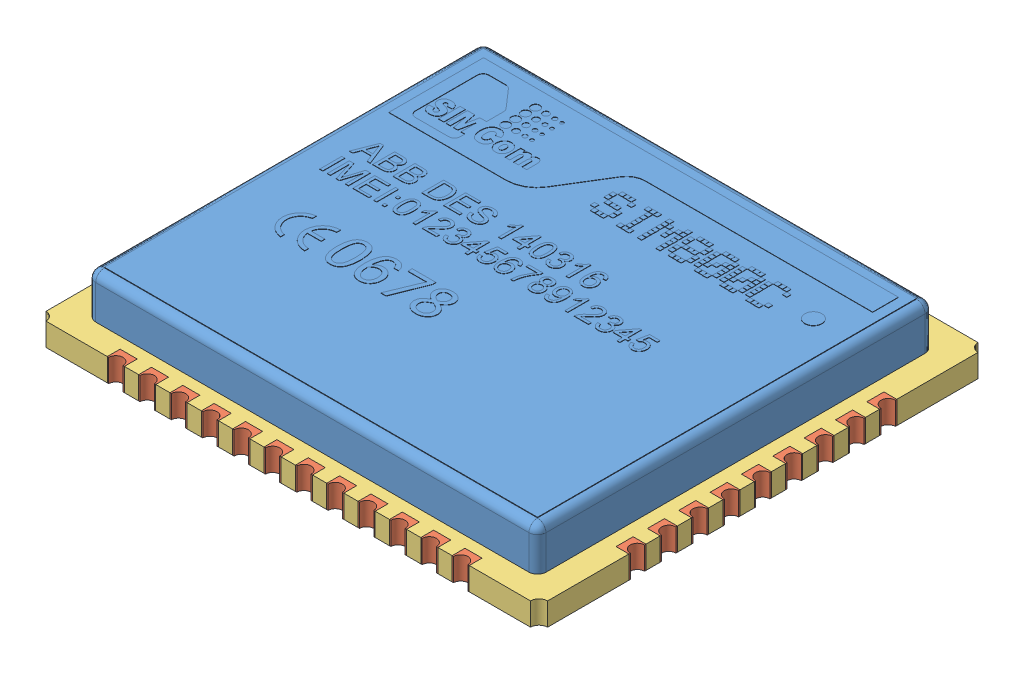
SolidWorks assembly User Library-SIM800C-1, configuration Défaut. Lengths in mm.
Overall size (17.6 2.34 15.7).
44 component instances, 3 part files, 128 mates.
Components (placement in the parent):
- User Library-SIM800C-1_SIM800C_Cup-1: User Library-SIM800C-1_SIM800C_Cup [Défaut] at (-74.7573 31.9435 0) size (15.8 1.53 13.9)
- User Library-SIM800C-1_SIM800C_pads-1: User Library-SIM800C-1_SIM800C_pads [Défaut] at (-80.8082 31.9435 -7.6815) x (1 0 0) z (0 0 -1) size (0.6 0.8 0.45)
- User Library-SIM800C-1_SIM800C_pcb-1: User Library-SIM800C-1_SIM800C_pcb [Défaut] at (-71.1269 31.9435 3.3608) x (1 0 0) z (0 0 -1) size (17.6 0.81 15.7)
- User Library-SIM800C-1_SIM800C_pads-2: User Library-SIM800C-1_SIM800C_pads [Défaut] at (-78.6082 31.9435 -7.6815) x (1 0 0) z (0 0 -1) size (0.6 0.8 0.45)
- User Library-SIM800C-1_SIM800C_pads-3: User Library-SIM800C-1_SIM800C_pads [Défaut] at (-79.7082 31.9435 -7.6815) x (1 0 0) z (0 0 -1) size (0.6 0.8 0.45)
- User Library-SIM800C-1_SIM800C_pads-4: User Library-SIM800C-1_SIM800C_pads [Défaut] at (-77.5082 31.9435 -7.6815) x (1 0 0) z (0 0 -1) size (0.6 0.8 0.45)
- User Library-SIM800C-1_SIM800C_pads-5: User Library-SIM800C-1_SIM800C_pads [Défaut] at (-76.4082 31.9435 -7.6815) x (1 0 0) z (0 0 -1) size (0.6 0.8 0.45)
- User Library-SIM800C-1_SIM800C_pads-6: User Library-SIM800C-1_SIM800C_pads [Défaut] at (-75.3082 31.9435 -7.6815) x (1 0 0) z (0 0 -1) size (0.6 0.8 0.45)
- User Library-SIM800C-1_SIM800C_pads-7: User Library-SIM800C-1_SIM800C_pads [Défaut] at (-74.2082 31.9435 -7.6815) x (1 0 0) z (0 0 -1) size (0.6 0.8 0.45)
- User Library-SIM800C-1_SIM800C_pads-8: User Library-SIM800C-1_SIM800C_pads [Défaut] at (-73.1082 31.9435 -7.6815) x (1 0 0) z (0 0 -1) size (0.6 0.8 0.45)
- User Library-SIM800C-1_SIM800C_pads-9: User Library-SIM800C-1_SIM800C_pads [Défaut] at (-72.0082 31.9435 -7.6815) x (1 0 0) z (0 0 -1) size (0.6 0.8 0.45)
- User Library-SIM800C-1_SIM800C_pads-10: User Library-SIM800C-1_SIM800C_pads [Défaut] at (-70.9082 31.9435 -7.6815) x (1 0 0) z (0 0 -1) size (0.6 0.8 0.45)
- User Library-SIM800C-1_SIM800C_pads-11: User Library-SIM800C-1_SIM800C_pads [Défaut] at (-69.8082 31.9435 -7.6815) x (1 0 0) z (0 0 -1) size (0.6 0.8 0.45)
- User Library-SIM800C-1_SIM800C_pads-12: User Library-SIM800C-1_SIM800C_pads [Défaut] at (-68.7082 31.9435 -7.6815) x (1 0 0) z (0 0 -1) size (0.6 0.8 0.45)
- User Library-SIM800C-1_SIM800C_pads-14: User Library-SIM800C-1_SIM800C_pads [Défaut] at (-66.1832 31.9435 -4.4565) x (0 0 1) z (1 0 0) size (0.6 0.8 0.45)
- User Library-SIM800C-1_SIM800C_pads-15: User Library-SIM800C-1_SIM800C_pads [Défaut] at (-66.1832 31.9435 -3.3565) x (0 0 1) z (1 0 0) size (0.6 0.8 0.45)
- User Library-SIM800C-1_SIM800C_pads-16: User Library-SIM800C-1_SIM800C_pads [Défaut] at (-66.1832 31.1435 -2.2565) x (0 0 -1) z (1 0 0) size (0.6 0.8 0.45)
- User Library-SIM800C-1_SIM800C_pads-17: User Library-SIM800C-1_SIM800C_pads [Défaut] at (-66.1832 31.9435 -1.1565) x (0 0 1) z (1 0 0) size (0.6 0.8 0.45)
- User Library-SIM800C-1_SIM800C_pads-18: User Library-SIM800C-1_SIM800C_pads [Défaut] at (-66.1832 31.9435 -0.0565) x (0 0 1) z (1 0 0) size (0.6 0.8 0.45)
- User Library-SIM800C-1_SIM800C_pads-19: User Library-SIM800C-1_SIM800C_pads [Défaut] at (-66.1832 31.9435 1.0435) x (0 0 1) z (1 0 0) size (0.6 0.8 0.45)
- User Library-SIM800C-1_SIM800C_pads-20: User Library-SIM800C-1_SIM800C_pads [Défaut] at (-66.1832 31.9435 2.1435) x (0 0 1) z (1 0 0) size (0.6 0.8 0.45)
- User Library-SIM800C-1_SIM800C_pads-21: User Library-SIM800C-1_SIM800C_pads [Défaut] at (-66.1832 31.9435 3.2435) x (0 0 1) z (1 0 0) size (0.6 0.8 0.45)
- User Library-SIM800C-1_SIM800C_pads-22: User Library-SIM800C-1_SIM800C_pads [Défaut] at (-66.1832 31.9435 4.3435) x (0 0 1) z (1 0 0) size (0.6 0.8 0.45)
- User Library-SIM800C-1_SIM800C_pads-23: User Library-SIM800C-1_SIM800C_pads [Défaut] at (-83.3332 31.9435 -4.4565) x (0 0 -1) z (-1 0 0) size (0.6 0.8 0.45)
- User Library-SIM800C-1_SIM800C_pads-24: User Library-SIM800C-1_SIM800C_pads [Défaut] at (-83.3332 31.1435 -3.3565) x (0 0 1) z (-1 0 0) size (0.6 0.8 0.45)
- User Library-SIM800C-1_SIM800C_pads-25: User Library-SIM800C-1_SIM800C_pads [Défaut] at (-83.3332 31.1435 -2.2565) x (0 0 1) z (-1 0 0) size (0.6 0.8 0.45)
- User Library-SIM800C-1_SIM800C_pads-26: User Library-SIM800C-1_SIM800C_pads [Défaut] at (-83.3332 31.1435 -1.1565) x (0 0 1) z (-1 0 0) size (0.6 0.8 0.45)
- User Library-SIM800C-1_SIM800C_pads-27: User Library-SIM800C-1_SIM800C_pads [Défaut] at (-83.3332 31.1435 -0.0565) x (0 0 1) z (-1 0 0) size (0.6 0.8 0.45)
- User Library-SIM800C-1_SIM800C_pads-28: User Library-SIM800C-1_SIM800C_pads [Défaut] at (-83.3332 31.1435 1.0435) x (0 0 1) z (-1 0 0) size (0.6 0.8 0.45)
- User Library-SIM800C-1_SIM800C_pads-29: User Library-SIM800C-1_SIM800C_pads [Défaut] at (-83.3332 31.1435 2.1435) x (0 0 1) z (-1 0 0) size (0.6 0.8 0.45)
- User Library-SIM800C-1_SIM800C_pads-30: User Library-SIM800C-1_SIM800C_pads [Défaut] at (-83.3332 31.1435 3.2435) x (0 0 1) z (-1 0 0) size (0.6 0.8 0.45)
- User Library-SIM800C-1_SIM800C_pads-31: User Library-SIM800C-1_SIM800C_pads [Défaut] at (-83.3332 31.1435 4.3435) x (0 0 1) z (-1 0 0) size (0.6 0.8 0.45)
- User Library-SIM800C-1_SIM800C_pads-32: User Library-SIM800C-1_SIM800C_pads [Défaut] at (-80.8082 31.9435 7.5685) x (-1 0 0) z (0 0 1) size (0.6 0.8 0.45)
- User Library-SIM800C-1_SIM800C_pads-33: User Library-SIM800C-1_SIM800C_pads [Défaut] at (-79.7082 31.1435 7.5685) size (0.6 0.8 0.45)
- User Library-SIM800C-1_SIM800C_pads-34: User Library-SIM800C-1_SIM800C_pads [Défaut] at (-78.6082 31.9435 7.5685) x (-1 0 0) z (0 0 1) size (0.6 0.8 0.45)
- User Library-SIM800C-1_SIM800C_pads-35: User Library-SIM800C-1_SIM800C_pads [Défaut] at (-77.5082 31.9435 7.5685) x (-1 0 0) z (0 0 1) size (0.6 0.8 0.45)
- User Library-SIM800C-1_SIM800C_pads-36: User Library-SIM800C-1_SIM800C_pads [Défaut] at (-76.4082 31.1435 7.5685) size (0.6 0.8 0.45)
- User Library-SIM800C-1_SIM800C_pads-37: User Library-SIM800C-1_SIM800C_pads [Défaut] at (-75.3082 31.1435 7.5685) size (0.6 0.8 0.45)
- User Library-SIM800C-1_SIM800C_pads-38: User Library-SIM800C-1_SIM800C_pads [Défaut] at (-74.2082 31.1435 7.5685) size (0.6 0.8 0.45)
- User Library-SIM800C-1_SIM800C_pads-39: User Library-SIM800C-1_SIM800C_pads [Défaut] at (-73.1082 31.1435 7.5685) size (0.6 0.8 0.45)
- User Library-SIM800C-1_SIM800C_pads-40: User Library-SIM800C-1_SIM800C_pads [Défaut] at (-72.0082 31.1435 7.5685) size (0.6 0.8 0.45)
- User Library-SIM800C-1_SIM800C_pads-41: User Library-SIM800C-1_SIM800C_pads [Défaut] at (-70.9082 31.1435 7.5685) size (0.6 0.8 0.45)
- User Library-SIM800C-1_SIM800C_pads-42: User Library-SIM800C-1_SIM800C_pads [Défaut] at (-69.8082 31.1435 7.5685) size (0.6 0.8 0.45)
- User Library-SIM800C-1_SIM800C_pads-43: User Library-SIM800C-1_SIM800C_pads [Défaut] at (-68.7082 31.1435 7.5685) size (0.6 0.8 0.45)
Mates (geometry in assembly coordinates):
- Coïncidente1: coincident: plane of User Library-SIM800C-1_SIM800C_pads-1 through (-81.1082 31.1435 -7.4565) normal (0 0 1); plane of User Library-SIM800C-1_SIM800C_pcb-1 through (-71.1269 31.1435 -7.4565) normal (0 0 -1)
- Coïncidente2: coincident: plane of User Library-SIM800C-1_SIM800C_pads-1 through (-80.5082 31.1435 -7.4565) normal (1 0 0); plane of User Library-SIM800C-1_SIM800C_pcb-1 through (-80.5082 31.1435 3.3608) normal (-1 0 0)
- Coïncidente3: coincident: plane of User Library-SIM800C-1_SIM800C_pads-1 through (-80.8082 31.1435 -7.9065) normal (0 -1 0); plane of User Library-SIM800C-1_SIM800C_pcb-1 through (-71.1269 31.1435 3.3608) normal (0 -1 0)
- Coïncidente13: coincident: plane of User Library-SIM800C-1_SIM800C_pcb-1 through (-71.1269 31.1435 -7.4565) normal (0 0 -1); plane of User Library-SIM800C-1_SIM800C_pads-3 through (-80.0082 31.1435 -7.4565) normal (0 0 1)
- Coïncidente14: coincident: plane of User Library-SIM800C-1_SIM800C_pcb-1 through (-79.4082 31.1435 3.3608) normal (-1 0 0); plane of User Library-SIM800C-1_SIM800C_pads-3 through (-79.4082 31.1435 -7.4565) normal (1 0 0)
- Coïncidente15: coincident: plane of User Library-SIM800C-1_SIM800C_pcb-1 through (-71.1269 31.1435 3.3608) normal (0 -1 0); plane of User Library-SIM800C-1_SIM800C_pads-3 through (-79.7082 31.1435 -7.9065) normal (0 -1 0)
- Coïncidente16: coincident: plane of User Library-SIM800C-1_SIM800C_pcb-1 through (-71.1269 31.1435 -7.4565) normal (0 0 -1); plane of User Library-SIM800C-1_SIM800C_pads-2 through (-78.9082 31.1435 -7.4565) normal (0 0 1)
- Coïncidente17: coincident: plane of User Library-SIM800C-1_SIM800C_pcb-1 through (-78.3082 31.1435 3.3608) normal (-1 0 0); plane of User Library-SIM800C-1_SIM800C_pads-2 through (-78.3082 31.1435 -7.4565) normal (1 0 0)
- Coïncidente18: coincident: plane of User Library-SIM800C-1_SIM800C_pcb-1 through (-71.1269 31.1435 3.3608) normal (0 -1 0); plane of User Library-SIM800C-1_SIM800C_pads-2 through (-78.6082 31.1435 -7.9065) normal (0 -1 0)
- Coïncidente19: coincident: plane of User Library-SIM800C-1_SIM800C_pcb-1 through (-71.1269 31.1435 -7.4565) normal (0 0 -1); plane of User Library-SIM800C-1_SIM800C_pads-4 through (-77.8082 31.1435 -7.4565) normal (0 0 1)
- Coïncidente20: coincident: plane of User Library-SIM800C-1_SIM800C_pcb-1 through (-77.2082 31.1435 3.3608) normal (-1 0 0); plane of User Library-SIM800C-1_SIM800C_pads-4 through (-77.2082 31.1435 -7.4565) normal (1 0 0)
- Coïncidente21: coincident: plane of User Library-SIM800C-1_SIM800C_pcb-1 through (-71.1269 31.1435 3.3608) normal (0 -1 0); plane of User Library-SIM800C-1_SIM800C_pads-4 through (-77.5082 31.1435 -7.9065) normal (0 -1 0)
- Coïncidente22: coincident: plane of User Library-SIM800C-1_SIM800C_pcb-1 through (-71.1269 31.1435 -7.4565) normal (0 0 -1); plane of User Library-SIM800C-1_SIM800C_pads-5 through (-76.7082 31.1435 -7.4565) normal (0 0 1)
- Coïncidente23: coincident: plane of User Library-SIM800C-1_SIM800C_pcb-1 through (-76.1082 31.1435 3.3608) normal (-1 0 0); plane of User Library-SIM800C-1_SIM800C_pads-5 through (-76.1082 31.1435 -7.4565) normal (1 0 0)
- Coïncidente24: coincident: plane of User Library-SIM800C-1_SIM800C_pcb-1 through (-71.1269 31.1435 3.3608) normal (0 -1 0); plane of User Library-SIM800C-1_SIM800C_pads-5 through (-76.4082 31.1435 -7.9065) normal (0 -1 0)
- Coïncidente25: coincident: plane of User Library-SIM800C-1_SIM800C_pcb-1 through (-75.0082 31.1435 3.3608) normal (-1 0 0); plane of User Library-SIM800C-1_SIM800C_pads-6 through (-75.0082 31.1435 -7.4565) normal (1 0 0)
- Coïncidente26: coincident: plane of User Library-SIM800C-1_SIM800C_pcb-1 through (-71.1269 31.1435 3.3608) normal (0 -1 0); plane of User Library-SIM800C-1_SIM800C_pads-6 through (-75.3082 31.1435 -7.9065) normal (0 -1 0)
- Coïncidente27: coincident: plane of User Library-SIM800C-1_SIM800C_pcb-1 through (-71.1269 31.1435 -7.4565) normal (0 0 -1); plane of User Library-SIM800C-1_SIM800C_pads-6 through (-75.6082 31.1435 -7.4565) normal (0 0 1)
- Coïncidente28: coincident: plane of User Library-SIM800C-1_SIM800C_pcb-1 through (-73.9082 31.1435 3.3608) normal (-1 0 0); plane of User Library-SIM800C-1_SIM800C_pads-7 through (-73.9082 31.1435 -7.4565) normal (1 0 0)
- Coïncidente29: coincident: plane of User Library-SIM800C-1_SIM800C_pcb-1 through (-71.1269 31.1435 3.3608) normal (0 -1 0); plane of User Library-SIM800C-1_SIM800C_pads-7 through (-74.2082 31.1435 -7.9065) normal (0 -1 0)
- Coïncidente30: coincident: plane of User Library-SIM800C-1_SIM800C_pcb-1 through (-71.1269 31.1435 -7.4565) normal (0 0 -1); plane of User Library-SIM800C-1_SIM800C_pads-7 through (-74.5082 31.1435 -7.4565) normal (0 0 1)
- Coïncidente31: coincident: plane of User Library-SIM800C-1_SIM800C_pcb-1 through (-72.8082 31.1435 3.3608) normal (-1 0 0); plane of User Library-SIM800C-1_SIM800C_pads-8 through (-72.8082 31.1435 -7.4565) normal (1 0 0)
- Coïncidente32: coincident: plane of User Library-SIM800C-1_SIM800C_pcb-1 through (-71.1269 31.1435 3.3608) normal (0 -1 0); plane of User Library-SIM800C-1_SIM800C_pads-8 through (-73.1082 31.1435 -7.9065) normal (0 -1 0)
- Coïncidente33: coincident: plane of User Library-SIM800C-1_SIM800C_pcb-1 through (-71.1269 31.1435 -7.4565) normal (0 0 -1); plane of User Library-SIM800C-1_SIM800C_pads-8 through (-73.4082 31.1435 -7.4565) normal (0 0 1)
- Coïncidente34: coincident: plane of User Library-SIM800C-1_SIM800C_pcb-1 through (-71.7082 31.1435 3.3608) normal (-1 0 0); plane of User Library-SIM800C-1_SIM800C_pads-9 through (-71.7082 31.1435 -7.4565) normal (1 0 0)
- Coïncidente35: coincident: plane of User Library-SIM800C-1_SIM800C_pcb-1 through (-71.1269 31.1435 3.3608) normal (0 -1 0); plane of User Library-SIM800C-1_SIM800C_pads-9 through (-72.0082 31.1435 -7.9065) normal (0 -1 0)
- Coïncidente36: coincident: plane of User Library-SIM800C-1_SIM800C_pcb-1 through (-71.1269 31.1435 -7.4565) normal (0 0 -1); plane of User Library-SIM800C-1_SIM800C_pads-9 through (-72.3082 31.1435 -7.4565) normal (0 0 1)
- Coïncidente37: coincident: plane of User Library-SIM800C-1_SIM800C_pcb-1 through (-70.6082 31.1435 3.3608) normal (-1 0 0); plane of User Library-SIM800C-1_SIM800C_pads-10 through (-70.6082 31.1435 -7.4565) normal (1 0 0)
- Coïncidente38: coincident: plane of User Library-SIM800C-1_SIM800C_pcb-1 through (-71.1269 31.1435 3.3608) normal (0 -1 0); plane of User Library-SIM800C-1_SIM800C_pads-10 through (-70.9082 31.1435 -7.9065) normal (0 -1 0)
- Coïncidente39: coincident: plane of User Library-SIM800C-1_SIM800C_pcb-1 through (-71.1269 31.1435 -7.4565) normal (0 0 -1); plane of User Library-SIM800C-1_SIM800C_pads-10 through (-71.2082 31.1435 -7.4565) normal (0 0 1)
- Coïncidente40: coincident: plane of User Library-SIM800C-1_SIM800C_pcb-1 through (-69.5082 31.1435 3.3608) normal (-1 0 0); plane of User Library-SIM800C-1_SIM800C_pads-11 through (-69.5082 31.1435 -7.4565) normal (1 0 0)
- Coïncidente41: coincident: plane of User Library-SIM800C-1_SIM800C_pcb-1 through (-71.1269 31.1435 3.3608) normal (0 -1 0); plane of User Library-SIM800C-1_SIM800C_pads-11 through (-69.8082 31.1435 -7.9065) normal (0 -1 0)
- Coïncidente42: coincident: plane of User Library-SIM800C-1_SIM800C_pcb-1 through (-71.1269 31.1435 -7.4565) normal (0 0 -1); plane of User Library-SIM800C-1_SIM800C_pads-11 through (-70.1082 31.1435 -7.4565) normal (0 0 1)
- Coïncidente43: coincident: plane of User Library-SIM800C-1_SIM800C_pcb-1 through (-68.4082 31.1435 3.3608) normal (-1 0 0); plane of User Library-SIM800C-1_SIM800C_pads-12 through (-68.4082 31.1435 -7.4565) normal (1 0 0)
- Coïncidente44: coincident: plane of User Library-SIM800C-1_SIM800C_pcb-1 through (-71.1269 31.1435 3.3608) normal (0 -1 0); plane of User Library-SIM800C-1_SIM800C_pads-12 through (-68.7082 31.1435 -7.9065) normal (0 -1 0)
- Coïncidente45: coincident: plane of User Library-SIM800C-1_SIM800C_pcb-1 through (-71.1269 31.1435 -7.4565) normal (0 0 -1); plane of User Library-SIM800C-1_SIM800C_pads-12 through (-69.0082 31.1435 -7.4565) normal (0 0 1)
- Coïncidente46: coincident: plane of User Library-SIM800C-1_SIM800C_pcb-1 through (-71.1269 31.1435 3.3608) normal (0 -1 0); circle of User Library-SIM800C-1_SIM800C_pads-14
- Coïncidente47: coincident: plane of User Library-SIM800C-1_SIM800C_pcb-1 through (-71.1269 31.1435 -4.1565) normal (0 0 -1); plane of User Library-SIM800C-1_SIM800C_pads-14 through (-66.4082 31.1435 -4.1565) normal (0 0 1)
- Coïncidente48: coincident: plane of User Library-SIM800C-1_SIM800C_pcb-1 through (-66.4082 31.1435 3.3608) normal (1 0 0); plane of User Library-SIM800C-1_SIM800C_pads-14 through (-66.4082 31.1435 -4.7565) normal (-1 0 0)
- Coïncidente49: coincident: plane of User Library-SIM800C-1_SIM800C_pcb-1 through (-71.1269 31.1435 3.3608) normal (0 -1 0); plane of User Library-SIM800C-1_SIM800C_pads-15 through (-65.9582 31.1435 -3.3565) normal (0 -1 0)
- Coïncidente50: coincident: plane of User Library-SIM800C-1_SIM800C_pcb-1 through (-71.1269 31.1435 -3.0565) normal (0 0 -1); plane of User Library-SIM800C-1_SIM800C_pads-15 through (-66.4082 31.1435 -3.0565) normal (0 0 1)
- Coïncidente51: coincident: plane of User Library-SIM800C-1_SIM800C_pcb-1 through (-66.4082 31.1435 3.3608) normal (1 0 0); plane of User Library-SIM800C-1_SIM800C_pads-15 through (-66.4082 31.1435 -3.6565) normal (-1 0 0)
- Coïncidente58: coincident: plane of User Library-SIM800C-1_SIM800C_pcb-1 through (-71.1269 31.1435 3.3608) normal (0 -1 0); plane of User Library-SIM800C-1_SIM800C_pads-16 through (-65.9582 31.1435 -2.2565) normal (0 -1 0)
- Coïncidente59: coincident: plane of User Library-SIM800C-1_SIM800C_pcb-1 through (-71.1269 31.1435 -1.9565) normal (0 0 -1); plane of User Library-SIM800C-1_SIM800C_pads-16 through (-66.4082 31.9435 -1.9565) normal (0 0 1)
- Coïncidente60: coincident: plane of User Library-SIM800C-1_SIM800C_pcb-1 through (-66.4082 31.1435 3.3608) normal (1 0 0); plane of User Library-SIM800C-1_SIM800C_pads-16 through (-66.4082 31.9435 -1.9565) normal (-1 0 0)
- Coïncidente61: coincident: plane of User Library-SIM800C-1_SIM800C_pcb-1 through (-71.1269 31.1435 3.3608) normal (0 -1 0); plane of User Library-SIM800C-1_SIM800C_pads-17 through (-65.9582 31.1435 -1.1565) normal (0 -1 0)
- Coïncidente62: coincident: plane of User Library-SIM800C-1_SIM800C_pcb-1 through (-71.1269 31.1435 -0.8565) normal (0 0 -1); plane of User Library-SIM800C-1_SIM800C_pads-17 through (-66.4082 31.1435 -0.8565) normal (0 0 1)
- Coïncidente63: coincident: plane of User Library-SIM800C-1_SIM800C_pcb-1 through (-66.4082 31.1435 3.3608) normal (1 0 0); plane of User Library-SIM800C-1_SIM800C_pads-17 through (-66.4082 31.1435 -1.4565) normal (-1 0 0)
- Coïncidente64: coincident: plane of User Library-SIM800C-1_SIM800C_pcb-1 through (-71.1269 31.1435 3.3608) normal (0 -1 0); plane of User Library-SIM800C-1_SIM800C_pads-18 through (-65.9582 31.1435 -0.0565) normal (0 -1 0)
- Coïncidente65: coincident: plane of User Library-SIM800C-1_SIM800C_pcb-1 through (-66.4082 31.1435 3.3608) normal (1 0 0); plane of User Library-SIM800C-1_SIM800C_pads-18 through (-66.4082 31.1435 -0.3565) normal (-1 0 0)
- Coïncidente66: coincident: plane of User Library-SIM800C-1_SIM800C_pcb-1 through (-71.1269 31.1435 0.2435) normal (0 0 -1); plane of User Library-SIM800C-1_SIM800C_pads-18 through (-66.4082 31.1435 0.2435) normal (0 0 1)
- Coïncidente67: coincident: plane of User Library-SIM800C-1_SIM800C_pcb-1 through (-71.1269 31.1435 3.3608) normal (0 -1 0); plane of User Library-SIM800C-1_SIM800C_pads-19 through (-65.9582 31.1435 1.0435) normal (0 -1 0)
- Coïncidente68: coincident: plane of User Library-SIM800C-1_SIM800C_pcb-1 through (-71.1269 31.1435 1.3435) normal (0 0 -1); plane of User Library-SIM800C-1_SIM800C_pads-19 through (-66.4082 31.1435 1.3435) normal (0 0 1)
- Coïncidente69: coincident: plane of User Library-SIM800C-1_SIM800C_pcb-1 through (-66.4082 31.1435 3.3608) normal (1 0 0); plane of User Library-SIM800C-1_SIM800C_pads-19 through (-66.4082 31.1435 0.7435) normal (-1 0 0)
- Coïncidente70: coincident: plane of User Library-SIM800C-1_SIM800C_pcb-1 through (-71.1269 31.1435 3.3608) normal (0 -1 0); plane of User Library-SIM800C-1_SIM800C_pads-20 through (-65.9582 31.1435 2.1435) normal (0 -1 0)
- Coïncidente71: coincident: plane of User Library-SIM800C-1_SIM800C_pcb-1 through (-71.1269 31.1435 2.4435) normal (0 0 -1); plane of User Library-SIM800C-1_SIM800C_pads-20 through (-66.4082 31.1435 2.4435) normal (0 0 1)
- Coïncidente72: coincident: plane of User Library-SIM800C-1_SIM800C_pcb-1 through (-66.4082 31.1435 3.3608) normal (1 0 0); plane of User Library-SIM800C-1_SIM800C_pads-20 through (-66.4082 31.1435 1.8435) normal (-1 0 0)
- Coïncidente73: coincident: plane of User Library-SIM800C-1_SIM800C_pcb-1 through (-71.1269 31.1435 3.5435) normal (0 0 -1); plane of User Library-SIM800C-1_SIM800C_pads-21 through (-66.4082 31.1435 3.5435) normal (0 0 1)
- Coïncidente74: coincident: plane of User Library-SIM800C-1_SIM800C_pcb-1 through (-71.1269 31.1435 3.3608) normal (0 -1 0); plane of User Library-SIM800C-1_SIM800C_pads-21 through (-65.9582 31.1435 3.2435) normal (0 -1 0)
- Coïncidente75: coincident: plane of User Library-SIM800C-1_SIM800C_pcb-1 through (-66.4082 31.1435 3.3608) normal (1 0 0); plane of User Library-SIM800C-1_SIM800C_pads-21 through (-66.4082 31.1435 2.9435) normal (-1 0 0)
- Coïncidente76: coincident: plane of User Library-SIM800C-1_SIM800C_pcb-1 through (-71.1269 31.1435 4.6435) normal (0 0 -1); plane of User Library-SIM800C-1_SIM800C_pads-22 through (-66.4082 31.1435 4.6435) normal (0 0 1)
- Coïncidente77: coincident: plane of User Library-SIM800C-1_SIM800C_pcb-1 through (-71.1269 31.1435 3.3608) normal (0 -1 0); plane of User Library-SIM800C-1_SIM800C_pads-22 through (-65.9582 31.1435 4.3435) normal (0 -1 0)
- Coïncidente78: coincident: plane of User Library-SIM800C-1_SIM800C_pcb-1 through (-66.4082 31.1435 3.3608) normal (1 0 0); plane of User Library-SIM800C-1_SIM800C_pads-22 through (-66.4082 31.1435 4.0435) normal (-1 0 0)
- Coïncidente79: coincident: plane of User Library-SIM800C-1_SIM800C_pcb-1 through (-71.1269 31.9435 3.3608) normal (0 1 0); plane of User Library-SIM800C-1_SIM800C_pads-23 through (-83.5582 31.9435 -4.4565) normal (0 1 0)
- Coïncidente80: coincident: plane of User Library-SIM800C-1_SIM800C_pcb-1 through (-71.1269 31.1435 -4.1565) normal (0 0 -1); plane of User Library-SIM800C-1_SIM800C_pads-23 through (-83.1082 31.1435 -4.1565) normal (0 0 1)
- Coïncidente81: coincident: plane of User Library-SIM800C-1_SIM800C_pcb-1 through (-83.1082 31.1435 3.3608) normal (-1 0 0); plane of User Library-SIM800C-1_SIM800C_pads-23 through (-83.1082 31.1435 -4.1565) normal (1 0 0)
- Coïncidente82: coincident: plane of User Library-SIM800C-1_SIM800C_pcb-1 through (-71.1269 31.9435 3.3608) normal (0 1 0); plane of User Library-SIM800C-1_SIM800C_pads-24 through (-83.5582 31.9435 -3.3565) normal (0 1 0)
- Coïncidente83: coincident: plane of User Library-SIM800C-1_SIM800C_pcb-1 through (-71.1269 31.1435 -3.0565) normal (0 0 -1); plane of User Library-SIM800C-1_SIM800C_pads-24 through (-83.1082 31.9435 -3.0565) normal (0 0 1)
- Coïncidente84: coincident: plane of User Library-SIM800C-1_SIM800C_pcb-1 through (-83.1082 31.1435 3.3608) normal (-1 0 0); plane of User Library-SIM800C-1_SIM800C_pads-24 through (-83.1082 31.9435 -3.6565) normal (1 0 0)
- Coïncidente85: coincident: plane of User Library-SIM800C-1_SIM800C_pcb-1 through (-71.1269 31.9435 3.3608) normal (0 1 0); plane of User Library-SIM800C-1_SIM800C_pads-25 through (-83.5582 31.9435 -2.2565) normal (0 1 0)
- Coïncidente86: coincident: plane of User Library-SIM800C-1_SIM800C_pcb-1 through (-71.1269 31.1435 -1.9565) normal (0 0 -1); plane of User Library-SIM800C-1_SIM800C_pads-25 through (-83.1082 31.9435 -1.9565) normal (0 0 1)
- Coïncidente87: coincident: plane of User Library-SIM800C-1_SIM800C_pcb-1 through (-83.1082 31.1435 3.3608) normal (-1 0 0); plane of User Library-SIM800C-1_SIM800C_pads-25 through (-83.1082 31.9435 -2.5565) normal (1 0 0)
- Coïncidente88: coincident: plane of User Library-SIM800C-1_SIM800C_pcb-1 through (-71.1269 31.9435 3.3608) normal (0 1 0); plane of User Library-SIM800C-1_SIM800C_pads-26 through (-83.5582 31.9435 -1.1565) normal (0 1 0)
- Coïncidente89: coincident: plane of User Library-SIM800C-1_SIM800C_pcb-1 through (-71.1269 31.1435 -0.8565) normal (0 0 -1); plane of User Library-SIM800C-1_SIM800C_pads-26 through (-83.1082 31.9435 -0.8565) normal (0 0 1)
- Coïncidente90: coincident: plane of User Library-SIM800C-1_SIM800C_pcb-1 through (-83.1082 31.1435 3.3608) normal (-1 0 0); plane of User Library-SIM800C-1_SIM800C_pads-26 through (-83.1082 31.9435 -1.4565) normal (1 0 0)
- Coïncidente91: coincident: plane of User Library-SIM800C-1_SIM800C_pcb-1 through (-71.1269 31.9435 3.3608) normal (0 1 0); plane of User Library-SIM800C-1_SIM800C_pads-27 through (-83.5582 31.9435 -0.0565) normal (0 1 0)
- Coïncidente92: coincident: plane of User Library-SIM800C-1_SIM800C_pcb-1 through (-71.1269 31.1435 0.2435) normal (0 0 -1); plane of User Library-SIM800C-1_SIM800C_pads-27 through (-83.1082 31.9435 0.2435) normal (0 0 1)
- Coïncidente93: coincident: plane of User Library-SIM800C-1_SIM800C_pcb-1 through (-83.1082 31.1435 3.3608) normal (-1 0 0); plane of User Library-SIM800C-1_SIM800C_pads-27 through (-83.1082 31.9435 -0.3565) normal (1 0 0)
- Coïncidente94: coincident: plane of User Library-SIM800C-1_SIM800C_pcb-1 through (-71.1269 31.9435 3.3608) normal (0 1 0); plane of User Library-SIM800C-1_SIM800C_pads-28 through (-83.5582 31.9435 1.0435) normal (0 1 0)
- Coïncidente95: coincident: plane of User Library-SIM800C-1_SIM800C_pcb-1 through (-71.1269 31.1435 1.3435) normal (0 0 -1); plane of User Library-SIM800C-1_SIM800C_pads-28 through (-83.1082 31.9435 1.3435) normal (0 0 1)
- Coïncidente96: coincident: plane of User Library-SIM800C-1_SIM800C_pcb-1 through (-83.1082 31.1435 3.3608) normal (-1 0 0); plane of User Library-SIM800C-1_SIM800C_pads-28 through (-83.1082 31.9435 0.7435) normal (1 0 0)
- Coïncidente98: coincident: plane of User Library-SIM800C-1_SIM800C_pcb-1 through (-71.1269 31.1435 2.4435) normal (0 0 -1); plane of User Library-SIM800C-1_SIM800C_pads-29 through (-83.1082 31.9435 2.4435) normal (0 0 1)
- Coïncidente99: coincident: plane of User Library-SIM800C-1_SIM800C_pcb-1 through (-83.1082 31.1435 3.3608) normal (-1 0 0); plane of User Library-SIM800C-1_SIM800C_pads-29 through (-83.1082 31.9435 1.8435) normal (1 0 0)
- Coïncidente100: coincident: plane of User Library-SIM800C-1_SIM800C_pcb-1 through (-71.1269 31.9435 3.3608) normal (0 1 0); plane of User Library-SIM800C-1_SIM800C_pads-29 through (-83.5582 31.9435 2.1435) normal (0 1 0)
- Coïncidente105: coincident: plane of User Library-SIM800C-1_SIM800C_pcb-1 through (-71.1269 31.9435 3.3608) normal (0 1 0); plane of User Library-SIM800C-1_SIM800C_pads-30 through (-83.5582 31.9435 3.2435) normal (0 1 0)
- Coïncidente106: coincident: plane of User Library-SIM800C-1_SIM800C_pcb-1 through (-71.1269 31.1435 3.5435) normal (0 0 -1); plane of User Library-SIM800C-1_SIM800C_pads-30 through (-83.1082 31.9435 3.5435) normal (0 0 1)
- Coïncidente107: coincident: plane of User Library-SIM800C-1_SIM800C_pcb-1 through (-83.1082 31.1435 3.3608) normal (-1 0 0); plane of User Library-SIM800C-1_SIM800C_pads-30 through (-83.1082 31.9435 2.9435) normal (1 0 0)
- Coïncidente108: coincident: plane of User Library-SIM800C-1_SIM800C_pcb-1 through (-71.1269 31.9435 3.3608) normal (0 1 0); plane of User Library-SIM800C-1_SIM800C_pads-31 through (-83.5582 31.9435 4.3435) normal (0 1 0)
- Coïncidente109: coincident: plane of User Library-SIM800C-1_SIM800C_pcb-1 through (-71.1269 31.1435 4.6435) normal (0 0 -1); plane of User Library-SIM800C-1_SIM800C_pads-31 through (-83.1082 31.9435 4.6435) normal (0 0 1)
- Coïncidente110: coincident: plane of User Library-SIM800C-1_SIM800C_pcb-1 through (-83.1082 31.1435 3.3608) normal (-1 0 0); plane of User Library-SIM800C-1_SIM800C_pads-31 through (-83.1082 31.9435 4.0435) normal (1 0 0)
- Coïncidente114: coincident: plane of User Library-SIM800C-1_SIM800C_pcb-1 through (-71.1269 31.9435 3.3608) normal (0 1 0); plane of User Library-SIM800C-1_SIM800C_pads-32 through (-80.8082 31.9435 7.7935) normal (0 1 0)
- Coïncidente115: coincident: plane of User Library-SIM800C-1_SIM800C_pcb-1 through (-80.5082 31.1435 3.3608) normal (-1 0 0); plane of User Library-SIM800C-1_SIM800C_pads-32 through (-80.5082 31.1435 7.3435) normal (1 0 0)
- Coïncidente116: coincident: plane of User Library-SIM800C-1_SIM800C_pcb-1 through (-71.1269 31.1435 7.3435) normal (0 0 1); plane of User Library-SIM800C-1_SIM800C_pads-32 through (-80.5082 31.1435 7.3435) normal (0 0 -1)
- Coïncidente117: coincident: plane of User Library-SIM800C-1_SIM800C_pcb-1 through (-71.1269 31.9435 3.3608) normal (0 1 0); plane of User Library-SIM800C-1_SIM800C_pads-33 through (-79.7082 31.9435 7.7935) normal (0 1 0)
- Coïncidente118: coincident: plane of User Library-SIM800C-1_SIM800C_pcb-1 through (-79.4082 31.1435 3.3608) normal (-1 0 0); plane of User Library-SIM800C-1_SIM800C_pads-33 through (-79.4082 31.9435 7.3435) normal (1 0 0)
- Coïncidente119: coincident: plane of User Library-SIM800C-1_SIM800C_pcb-1 through (-71.1269 31.1435 7.3435) normal (0 0 1); plane of User Library-SIM800C-1_SIM800C_pads-33 through (-80.0082 31.9435 7.3435) normal (0 0 -1)
- Coïncidente120: coincident: plane of User Library-SIM800C-1_SIM800C_pcb-1 through (-71.1269 31.9435 3.3608) normal (0 1 0); plane of User Library-SIM800C-1_SIM800C_pads-34 through (-78.6082 31.9435 7.7935) normal (0 1 0)
- Coïncidente121: coincident: plane of User Library-SIM800C-1_SIM800C_pcb-1 through (-78.3082 31.1435 3.3608) normal (-1 0 0); plane of User Library-SIM800C-1_SIM800C_pads-34 through (-78.3082 31.1435 7.3435) normal (1 0 0)
- Coïncidente122: coincident: plane of User Library-SIM800C-1_SIM800C_pcb-1 through (-71.1269 31.1435 7.3435) normal (0 0 1); plane of User Library-SIM800C-1_SIM800C_pads-34 through (-78.3082 31.1435 7.3435) normal (0 0 -1)
- Coïncidente123: coincident: plane of User Library-SIM800C-1_SIM800C_pcb-1 through (-71.1269 31.9435 3.3608) normal (0 1 0); plane of User Library-SIM800C-1_SIM800C_pads-35 through (-77.5082 31.9435 7.7935) normal (0 1 0)
- Coïncidente124: coincident: plane of User Library-SIM800C-1_SIM800C_pcb-1 through (-77.2082 31.1435 3.3608) normal (-1 0 0); plane of User Library-SIM800C-1_SIM800C_pads-35 through (-77.2082 31.1435 7.3435) normal (1 0 0)
- Coïncidente125: coincident: plane of User Library-SIM800C-1_SIM800C_pcb-1 through (-71.1269 31.1435 7.3435) normal (0 0 1); plane of User Library-SIM800C-1_SIM800C_pads-35 through (-77.2082 31.1435 7.3435) normal (0 0 -1)
- Coïncidente126: coincident: plane of User Library-SIM800C-1_SIM800C_pcb-1 through (-71.1269 31.9435 3.3608) normal (0 1 0); plane of User Library-SIM800C-1_SIM800C_pads-36 through (-76.4082 31.9435 7.7935) normal (0 1 0)
- Coïncidente127: coincident: plane of User Library-SIM800C-1_SIM800C_pcb-1 through (-76.1082 31.1435 3.3608) normal (-1 0 0); plane of User Library-SIM800C-1_SIM800C_pads-36 through (-76.1082 31.9435 7.3435) normal (1 0 0)
- Coïncidente128: coincident: plane of User Library-SIM800C-1_SIM800C_pcb-1 through (-71.1269 31.1435 7.3435) normal (0 0 1); plane of User Library-SIM800C-1_SIM800C_pads-36 through (-76.7082 31.9435 7.3435) normal (0 0 -1)
- Coïncidente129: coincident: plane of User Library-SIM800C-1_SIM800C_pcb-1 through (-71.1269 31.9435 3.3608) normal (0 1 0); plane of User Library-SIM800C-1_SIM800C_pads-37 through (-75.3082 31.9435 7.7935) normal (0 1 0)
- Coïncidente130: coincident: plane of User Library-SIM800C-1_SIM800C_pcb-1 through (-75.0082 31.1435 3.3608) normal (-1 0 0); plane of User Library-SIM800C-1_SIM800C_pads-37 through (-75.0082 31.9435 7.3435) normal (1 0 0)
- Coïncidente131: coincident: plane of User Library-SIM800C-1_SIM800C_pcb-1 through (-71.1269 31.1435 7.3435) normal (0 0 1); plane of User Library-SIM800C-1_SIM800C_pads-37 through (-75.6082 31.9435 7.3435) normal (0 0 -1)
- Coïncidente132: coincident: plane of User Library-SIM800C-1_SIM800C_pcb-1 through (-71.1269 31.9435 3.3608) normal (0 1 0); plane of User Library-SIM800C-1_SIM800C_pads-38 through (-74.2082 31.9435 7.7935) normal (0 1 0)
- Coïncidente133: coincident: plane of User Library-SIM800C-1_SIM800C_pcb-1 through (-73.9082 31.1435 3.3608) normal (-1 0 0); plane of User Library-SIM800C-1_SIM800C_pads-38 through (-73.9082 31.9435 7.3435) normal (1 0 0)
- Coïncidente134: coincident: plane of User Library-SIM800C-1_SIM800C_pcb-1 through (-71.1269 31.1435 7.3435) normal (0 0 1); plane of User Library-SIM800C-1_SIM800C_pads-38 through (-74.5082 31.9435 7.3435) normal (0 0 -1)
- Coïncidente135: coincident: plane of User Library-SIM800C-1_SIM800C_pcb-1 through (-71.1269 31.9435 3.3608) normal (0 1 0); plane of User Library-SIM800C-1_SIM800C_pads-39 through (-73.1082 31.9435 7.7935) normal (0 1 0)
- Coïncidente136: coincident: plane of User Library-SIM800C-1_SIM800C_pcb-1 through (-72.8082 31.1435 3.3608) normal (-1 0 0); plane of User Library-SIM800C-1_SIM800C_pads-39 through (-72.8082 31.9435 7.3435) normal (1 0 0)
- Coïncidente137: coincident: plane of User Library-SIM800C-1_SIM800C_pcb-1 through (-71.1269 31.1435 7.3435) normal (0 0 1); plane of User Library-SIM800C-1_SIM800C_pads-39 through (-73.4082 31.9435 7.3435) normal (0 0 -1)
- Coïncidente138: coincident: plane of User Library-SIM800C-1_SIM800C_pcb-1 through (-71.1269 31.9435 3.3608) normal (0 1 0); plane of User Library-SIM800C-1_SIM800C_pads-40 through (-72.0082 31.9435 7.7935) normal (0 1 0)
- Coïncidente139: coincident: plane of User Library-SIM800C-1_SIM800C_pcb-1 through (-71.7082 31.1435 3.3608) normal (-1 0 0); plane of User Library-SIM800C-1_SIM800C_pads-40 through (-71.7082 31.9435 7.3435) normal (1 0 0)
- Coïncidente140: coincident: plane of User Library-SIM800C-1_SIM800C_pcb-1 through (-71.1269 31.1435 7.3435) normal (0 0 1); plane of User Library-SIM800C-1_SIM800C_pads-40 through (-72.3082 31.9435 7.3435) normal (0 0 -1)
- Coïncidente141: coincident: plane of User Library-SIM800C-1_SIM800C_pcb-1 through (-71.1269 31.9435 3.3608) normal (0 1 0); plane of User Library-SIM800C-1_SIM800C_pads-41 through (-70.9082 31.9435 7.7935) normal (0 1 0)
- Coïncidente142: coincident: plane of User Library-SIM800C-1_SIM800C_pcb-1 through (-70.6082 31.1435 3.3608) normal (-1 0 0); plane of User Library-SIM800C-1_SIM800C_pads-41 through (-70.6082 31.9435 7.3435) normal (1 0 0)
- Coïncidente143: coincident: plane of User Library-SIM800C-1_SIM800C_pcb-1 through (-71.1269 31.1435 7.3435) normal (0 0 1); plane of User Library-SIM800C-1_SIM800C_pads-41 through (-71.2082 31.9435 7.3435) normal (0 0 -1)
- Coïncidente144: coincident: plane of User Library-SIM800C-1_SIM800C_pcb-1 through (-71.1269 31.9435 3.3608) normal (0 1 0); plane of User Library-SIM800C-1_SIM800C_pads-42 through (-69.8082 31.9435 7.7935) normal (0 1 0)
- Coïncidente145: coincident: plane of User Library-SIM800C-1_SIM800C_pcb-1 through (-69.5082 31.1435 3.3608) normal (-1 0 0); plane of User Library-SIM800C-1_SIM800C_pads-42 through (-69.5082 31.9435 7.3435) normal (1 0 0)
- Coïncidente146: coincident: plane of User Library-SIM800C-1_SIM800C_pcb-1 through (-71.1269 31.1435 7.3435) normal (0 0 1); plane of User Library-SIM800C-1_SIM800C_pads-42 through (-70.1082 31.9435 7.3435) normal (0 0 -1)
- Coïncidente147: coincident: plane of User Library-SIM800C-1_SIM800C_pcb-1 through (-71.1269 31.9435 3.3608) normal (0 1 0); plane of User Library-SIM800C-1_SIM800C_pads-43 through (-68.7082 31.9435 7.7935) normal (0 1 0)
- Coïncidente148: coincident: plane of User Library-SIM800C-1_SIM800C_pcb-1 through (-68.4082 31.1435 3.3608) normal (-1 0 0); plane of User Library-SIM800C-1_SIM800C_pads-43 through (-68.4082 31.9435 7.3435) normal (1 0 0)
- Coïncidente149: coincident: plane of User Library-SIM800C-1_SIM800C_pcb-1 through (-71.1269 31.1435 7.3435) normal (0 0 1); plane of User Library-SIM800C-1_SIM800C_pads-43 through (-69.0082 31.9435 7.3435) normal (0 0 -1)
- Coïncidente150: coincident: plane of User Library-SIM800C-1_SIM800C_Cup-1 through (-74.7573 31.9435 0) normal (0 -1 0); plane of User Library-SIM800C-1_SIM800C_pcb-1 through (-71.1269 31.9435 3.3608) normal (0 1 0)
- Parallèle7: parallel: plane of User Library-SIM800C-1_SIM800C_Cup-1 through (-82.6573 33.4435 -6.95) normal (-1 0 0); plane of User Library-SIM800C-1_SIM800C_pcb-1 through (-83.5582 31.1435 3.3608) normal (-1 0 0)
